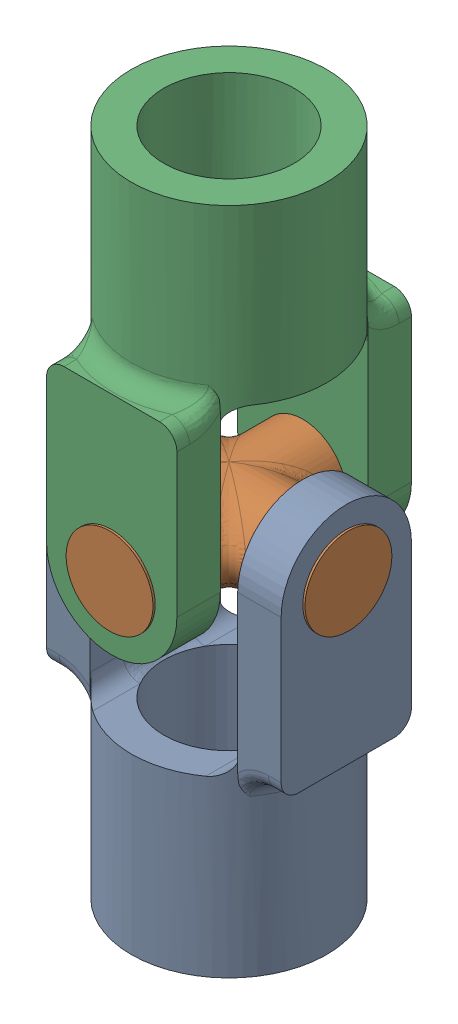
SolidWorks assembly Single U-Joint, configuration Default. Lengths in mm.
Overall size (34.92 97.79 34.92).
3 component instances, 2 part files, 4 mates.
Components (placement in the parent):
- 230018-1: 230018 [Default] at origin size (34.29 58.42 28.57)
- 230019-1: 230019 [Default] at (0 23.495 0) size (34.92 12.7 34.92)
- 230018-2: 230018 [Default] at (0 46.99 0) x (0 0 -1) z (-1 0 0) size (34.29 58.42 28.57)
Mates (geometry in assembly coordinates):
- Concentric1: concentric anti-aligned: cylinder of U-Joint Housing-1 through (-17.145 23.495 0) axis (1 0 0) radius 6.35; cylinder of U-Joint Cross-1 through (17.4625 23.495 0) axis (-1 0 0) radius 6.35
- Width1: width anti-aligned: plane of U-Joint Cross-1 through (17.4625 23.495 0) normal (1 0 0); plane of U-Joint Cross-1 through (-17.4625 23.495 0) normal (-1 0 0); plane of U-Joint Housing-1 through (-17.145 0 9.525) normal (-1 0 0); plane of U-Joint Housing-1 through (17.145 0 9.525) normal (1 0 0)
- Concentric2: concentric aligned: cylinder of U-Joint Cross-1 through (0 23.495 17.4625) axis (0 0 -1) radius 6.35; cylinder of U-Joint Housing-2 through (0 23.495 17.145) axis (0 0 -1) radius 6.35
- Width2: width anti-aligned: plane of U-Joint Housing-2 through (-9.525 46.99 17.145) normal (0 0 1); plane of U-Joint Housing-2 through (-9.525 46.99 -17.145) normal (0 0 -1); plane of U-Joint Cross-1 through (0 23.495 -17.4625) normal (0 0 -1); plane of U-Joint Cross-1 through (0 23.495 17.4625) normal (0 0 1)
